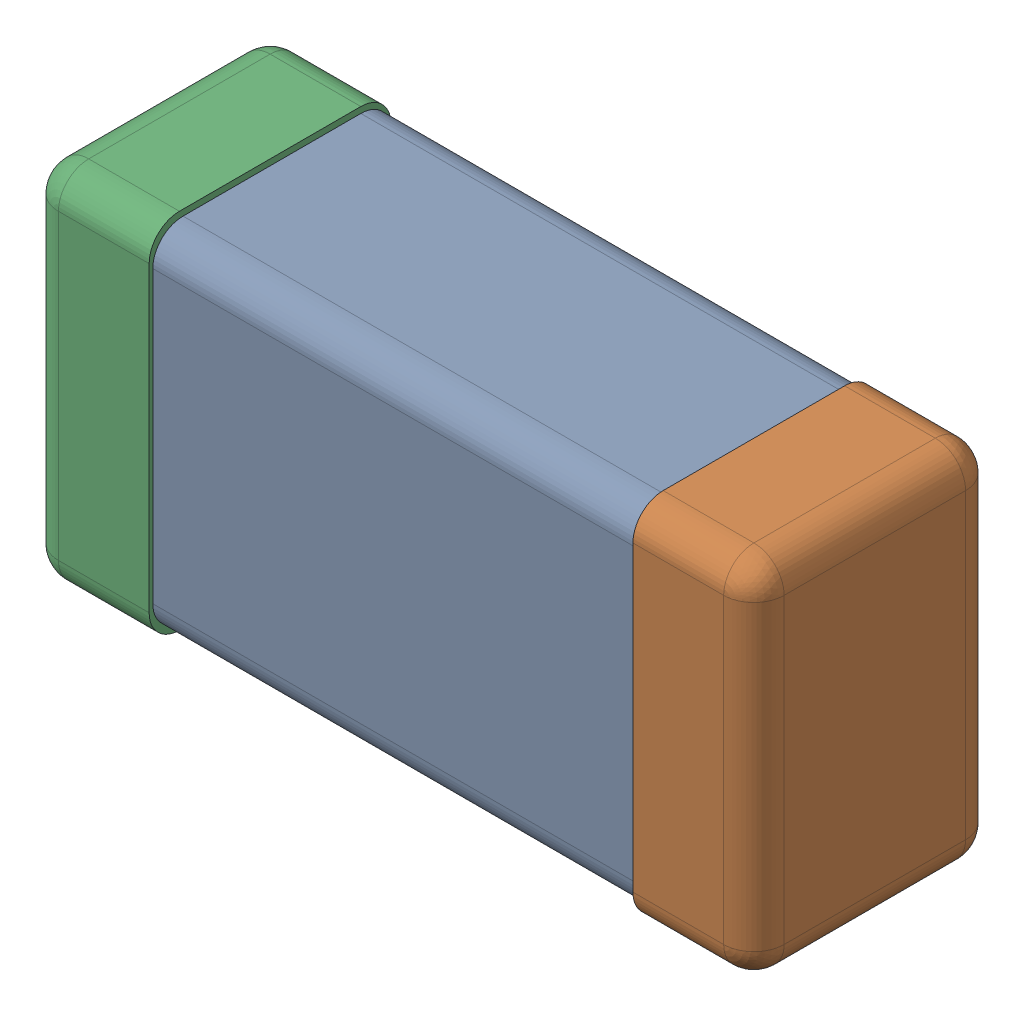
SolidWorks assembly C0201_020_16, configuration Standard. Lengths in mm.
Overall size (0.6 0.3 0.2).
4 component instances, 3 part files, 0 mates.
Components (placement in the parent):
- C0201_020_17-1: C0201_020_17 [Standard] at origin size (0.6 0.3 0.2)
  - Part 3_2-1: Part 3_2 [Standard] at (0 0 -7.3015) size (0.5 0.29 0.2)
  - Part 2_2-1: Part 2_2 [Standard] at (0 0 -7.3) size (0.1 0.3 0.2)
  - Part 1_2-1: Part 1_2 [Standard] at (0 0 -7.3) size (0.1 0.3 0.2)
